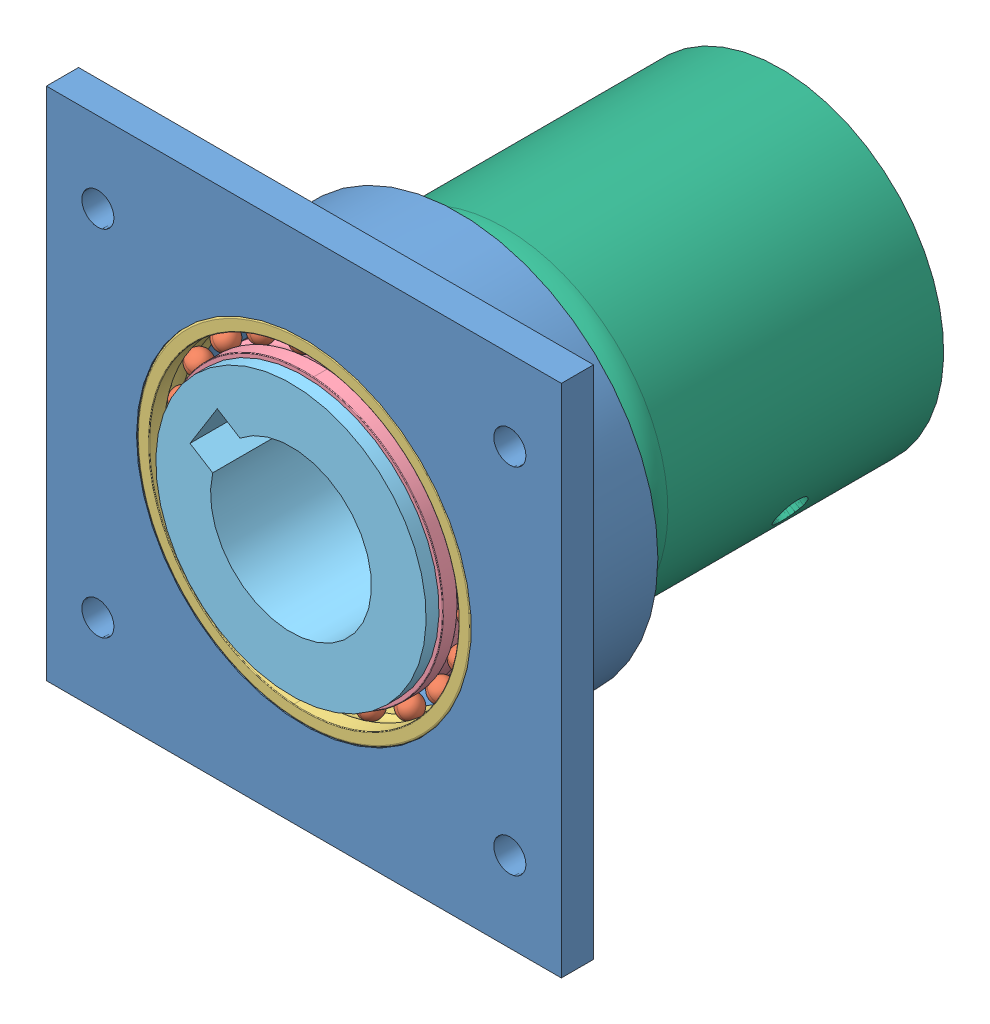
SolidWorks assembly Forearm mounting assembly, configuration Default. Lengths in mm.
Overall size (80 80 76).
51 component instances, 6 part files, 8 mates.
Components (placement in the parent):
- Forearm mount-1: Forearm mount [Default] at (23.4598 35.5842 33.2293) size (80 90 49)
- 61808-1: 61808 [Default] at (23.4598 35.5842 50.2293) x (0 0 1) z (0.066698 0.997773 0) size (7 52 52)
  - 61808_25-1: 61808_25 [Default] x (1 0 0) z (0 -0.294755 0.955573) size (3.5 3.5 3.5)
  - 61808_25-2: 61808_25 [Default] x (1 0 0) z (0 -0.56332 0.826239) size (3.5 3.5 3.5)
  - 61808_25-3: 61808_25 [Default] x (1 0 0) z (0 -0.781831 0.62349) size (3.5 3.5 3.5)
  - 61808_25-4: 61808_25 [Default] x (1 0 0) z (0 -0.930874 0.365341) size (3.5 3.5 3.5)
  - 61808_25-5: 61808_25 [Default] x (1 0 0) z (0 -0.997204 0.07473) size (3.5 3.5 3.5)
  - 61808_25-6: 61808_25 [Default] x (1 0 0) z (0 -0.974928 -0.222521) size (3.5 3.5 3.5)
  - 61808_25-7: 61808_25 [Default] x (1 0 0) z (0 -0.866025 -0.5) size (3.5 3.5 3.5)
  - 61808_25-8: 61808_25 [Default] x (1 0 0) z (0 -0.680173 -0.733052) size (3.5 3.5 3.5)
  - 61808_25-9: 61808_25 [Default] x (1 0 0) z (0 -0.433884 -0.900969) size (3.5 3.5 3.5)
  - 61808_25-10: 61808_25 [Default] x (1 0 0) z (0 -0.149042 -0.988831) size (3.5 3.5 3.5)
  - 61808_25-11: 61808_25 [Default] x (1 0 0) z (0 0.149042 -0.988831) size (3.5 3.5 3.5)
  - 61808_25-12: 61808_25 [Default] x (1 0 0) z (0 0.433884 -0.900969) size (3.5 3.5 3.5)
  - 61808_25-13: 61808_25 [Default] x (1 0 0) z (0 0.680173 -0.733052) size (3.5 3.5 3.5)
  - 61808_25-14: 61808_25 [Default] x (1 0 0) z (0 0.866025 -0.5) size (3.5 3.5 3.5)
  - 61808_25-15: 61808_25 [Default] x (1 0 0) z (0 0.974928 -0.222521) size (3.5 3.5 3.5)
  - 61808_25-16: 61808_25 [Default] x (1 0 0) z (0 0.997204 0.07473) size (3.5 3.5 3.5)
  - 61808_25-17: 61808_25 [Default] x (1 0 0) z (0 0.930874 0.365341) size (3.5 3.5 3.5)
  - 61808_25-18: 61808_25 [Default] x (1 0 0) z (0 0.781831 0.62349) size (3.5 3.5 3.5)
  - 61808_25-19: 61808_25 [Default] x (1 0 0) z (0 0.56332 0.826239) size (3.5 3.5 3.5)
  - 61808_25-20: 61808_25 [Default] x (1 0 0) z (0 0.294755 0.955573) size (3.5 3.5 3.5)
  - 61808_25-21: 61808_25 [Default] at origin size (3.5 3.5 3.5)
  - 61808_47-1: 61808_47 [Default] at origin size (7 52 52)
  - 61808_49-1: 61808_49 [Default] at origin size (7 43.21 43.21)
- 61808-2: 61808 [Default] at (23.4598 35.5842 33.2293) x (0 0 1) z (-0.983327 0.181844 0) size (7 52 52)
  - 61808_25-1: 61808_25 [Default] x (1 0 0) z (0 -0.294755 0.955573) size (3.5 3.5 3.5)
  - 61808_25-2: 61808_25 [Default] x (1 0 0) z (0 -0.56332 0.826239) size (3.5 3.5 3.5)
  - 61808_25-3: 61808_25 [Default] x (1 0 0) z (0 -0.781831 0.62349) size (3.5 3.5 3.5)
  - 61808_25-4: 61808_25 [Default] x (1 0 0) z (0 -0.930874 0.365341) size (3.5 3.5 3.5)
  - 61808_25-5: 61808_25 [Default] x (1 0 0) z (0 -0.997204 0.07473) size (3.5 3.5 3.5)
  - 61808_25-6: 61808_25 [Default] x (1 0 0) z (0 -0.974928 -0.222521) size (3.5 3.5 3.5)
  - 61808_25-7: 61808_25 [Default] x (1 0 0) z (0 -0.866025 -0.5) size (3.5 3.5 3.5)
  - 61808_25-8: 61808_25 [Default] x (1 0 0) z (0 -0.680173 -0.733052) size (3.5 3.5 3.5)
  - 61808_25-9: 61808_25 [Default] x (1 0 0) z (0 -0.433884 -0.900969) size (3.5 3.5 3.5)
  - 61808_25-10: 61808_25 [Default] x (1 0 0) z (0 -0.149042 -0.988831) size (3.5 3.5 3.5)
  - 61808_25-11: 61808_25 [Default] x (1 0 0) z (0 0.149042 -0.988831) size (3.5 3.5 3.5)
  - 61808_25-12: 61808_25 [Default] x (1 0 0) z (0 0.433884 -0.900969) size (3.5 3.5 3.5)
  - 61808_25-13: 61808_25 [Default] x (1 0 0) z (0 0.680173 -0.733052) size (3.5 3.5 3.5)
  - 61808_25-14: 61808_25 [Default] x (1 0 0) z (0 0.866025 -0.5) size (3.5 3.5 3.5)
  - 61808_25-15: 61808_25 [Default] x (1 0 0) z (0 0.974928 -0.222521) size (3.5 3.5 3.5)
  - 61808_25-16: 61808_25 [Default] x (1 0 0) z (0 0.997204 0.07473) size (3.5 3.5 3.5)
  - 61808_25-17: 61808_25 [Default] x (1 0 0) z (0 0.930874 0.365341) size (3.5 3.5 3.5)
  - 61808_25-18: 61808_25 [Default] x (1 0 0) z (0 0.781831 0.62349) size (3.5 3.5 3.5)
  - 61808_25-19: 61808_25 [Default] x (1 0 0) z (0 0.56332 0.826239) size (3.5 3.5 3.5)
  - 61808_25-20: 61808_25 [Default] x (1 0 0) z (0 0.294755 0.955573) size (3.5 3.5 3.5)
  - 61808_25-21: 61808_25 [Default] at origin size (3.5 3.5 3.5)
  - 61808_47-1: 61808_47 [Default] at origin size (7 52 52)
  - 61808_49-1: 61808_49 [Default] at origin size (7 43.21 43.21)
- Forearm shaft coupler-1: Forearm shaft coupler [Default] at (23.4598 35.5842 59.2293) x (-0.529669 -0.848204 0) z (0 0 -1) size (42 42 76)
- Forearm housing-1: Forearm housing [Default] at (23.4598 35.5842 33.2293) x (0 0 -1) z (0.529669 0.848204 0) size (50 50.8 50.8)
Mates (geometry in assembly coordinates):
- Concentric1: concentric anti-aligned: cylinder of Forearm mount-1 through (23.4598 35.5842 57.2293) axis (0 0 -1) radius 26; cylinder of 61808-1/61808_49-1 through (23.4598 35.5842 150.2293) axis (0 0 1) radius 20
- Distance1: distance = 0 mm anti-aligned: plane of Forearm mount-1 through (23.4598 35.5842 50.2293) normal (0 0 1); plane of 61808-1/61808_47-1 through (49.1026 33.87 50.2293) normal (0 0 -1)
- Concentric2: concentric anti-aligned: cylinder of Forearm mount-1 through (23.4598 35.5842 40.2293) axis (0 0 -1) radius 26; cylinder of 61808-2/61808_49-1 through (23.4598 35.5842 133.2293) axis (0 0 1) radius 20
- Distance2: distance = 0 mm anti-aligned: plane of Forearm mount-1 through (23.4598 35.5842 40.2293) normal (0 0 -1); plane of 61808-2/61808_47-1 through (27.8513 59.3315 40.2293) normal (0 0 1)
- Concentric3: concentric anti-aligned: cylinder of Forearm mount-1 through (23.4598 35.5842 50.2293) axis (0 0 -1) radius 25; cylinder of Forearm shaft coupler-1 through (23.4598 35.5842 -16.7707) axis (0 0 1) radius 12.5
- Coincident1: coincident anti-aligned: plane of 61808-1/61808_49-1 through (43.7146 34.2302 57.2293) normal (0 0 1); plane of Forearm shaft coupler-1 through (23.4598 35.5842 57.2293) normal (0 0 -1)
- Concentric4: concentric aligned: cylinder of Forearm shaft coupler-1 through (23.4598 35.5842 -16.7707) axis (0 0 1) radius 20; cylinder of Forearm housing-1 through (23.4598 35.5842 -16.7707) axis (0 0 1) radius 20
- Concentric5: concentric aligned: cylinder of Forearm shaft coupler-1 through (40.4239 24.9908 3.2293) axis (0.848204 -0.529669 0) radius 2.5; cylinder of Forearm housing-1 through (45.0042 22.1306 3.2293) axis (0.848204 -0.529669 0) radius 2.5
